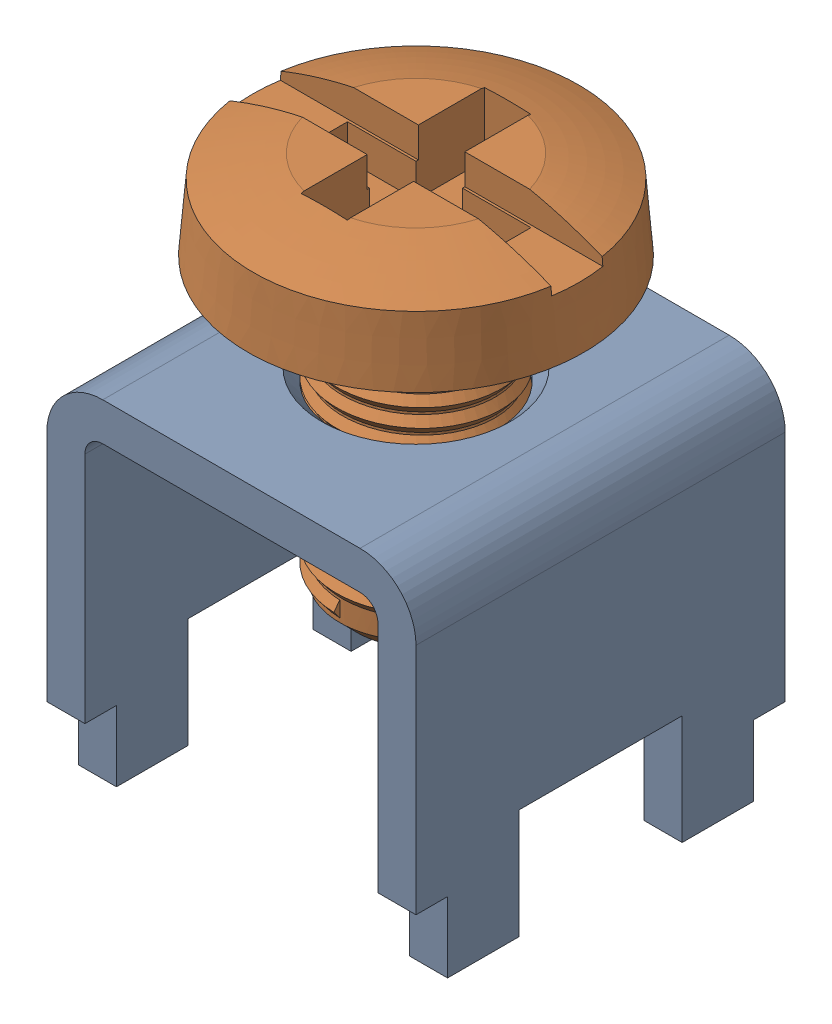
SolidWorks assembly PART_ServoPowerModule_ScrewTerminalAssembly, configuration Default. Lengths in mm.
Overall size (7.87 11.69 7.87).
2 component instances, 2 part files, 0 mates.
Components (placement in the parent):
- PART_ServoPowerModule_ScrewTerminalBase-1: PART_ServoPowerModule_ScrewTerminalBase [Default] at (3.4868 6.6312 8.3972) size (7.87 7.68 7.87)
- PART_ServoPowerModule_ScrewTerminalScrew-1: PART_ServoPowerModule_ScrewTerminalScrew [Default] at (3.5041 -1.1314 8.5263) x (0.998152 0 -0.060771) z (0.060771 0 0.998152) size (7.16 8.3 7.16)
